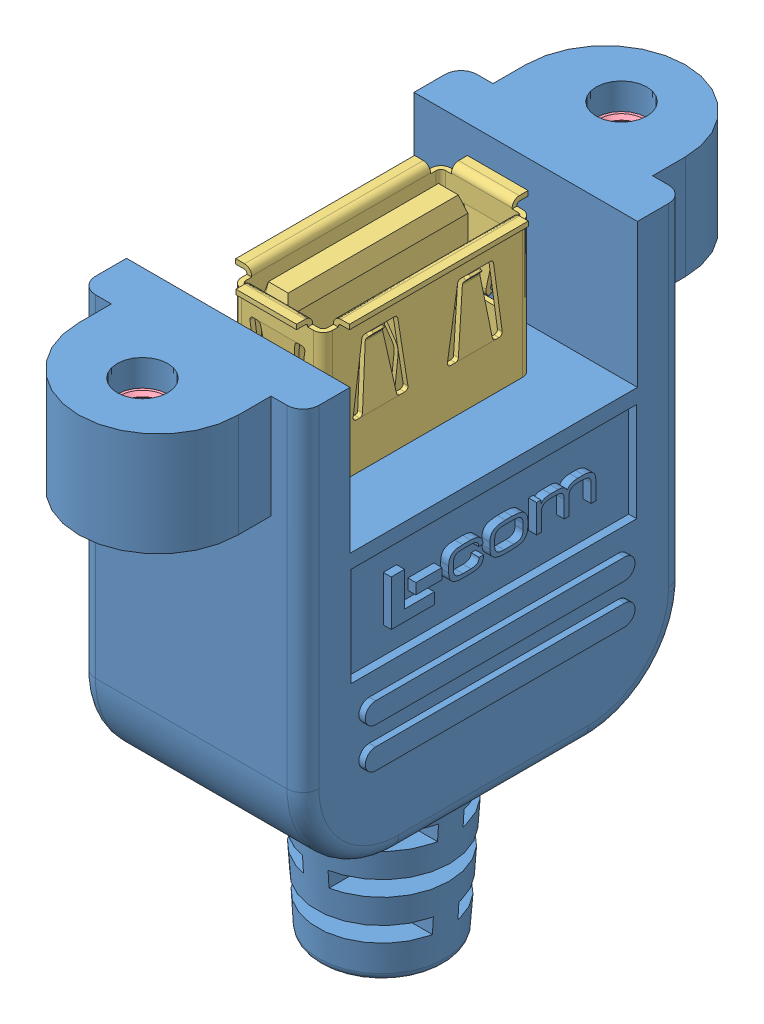
SolidWorks assembly UPMAA-xM - CONNECTOR, USB, TYPE A FEMALE BULKHEAD TO TYPE A MALE, configuration Bulkhead Connector Only. Lengths in mm.
Overall size (14.8 37.5 38).
9 component instances, 5 part files, 0 mates.
Components (placement in the parent):
- 1AL08-098_6 INCH-1: 1AL08-098_6 INCH [Default] x (0 0 1) z (0 1 0) (suppressed, hidden)
- MTN-157_NEW LOGO-1: MTN-157_NEW LOGO [Default] at (0 105.3 0) x (0 0 -1) z (0 1 0) size (38 14.8 37.5)
  - MTN-157_NEW L-COM LOGO-1: MTN-157_NEW L-COM LOGO [Default] at origin size (38 14.8 37.5)
  - MTN-268-1: MTN-268 [Default] at (0 0 -11.684) x (-1 0 0) z (0 0 1) size (19.05 9.91 24.89)
    - MTN-268-1: MTN-268 [Default] at origin size (19.05 9.91 13.21)
    - 1AA05-008(USB A TYPE FEMALE SOLDER TYPE)-1: 1AA05-008(USB A TYPE FEMALE SOLDER TYPE) [Default] at (0 0 -2.616) x (-1 0 0) z (0 0 1) size (14.5 7.12 17.8)
  - STKB-440-4-1: STKB-440-4 [Default] at (-15 0 -4.8375) size (4.78 4.78 3.17)
  - STKB-440-4-2: STKB-440-4 [Default] at (15 0 -4.8375) size (4.78 4.78 3.17)
- 3AB06-004_ec-comm-1: 3AB06-004_ec-comm [Default] at (0 -93.4491 0) x (0 0 -1) z (0 1 0) (suppressed, hidden)
